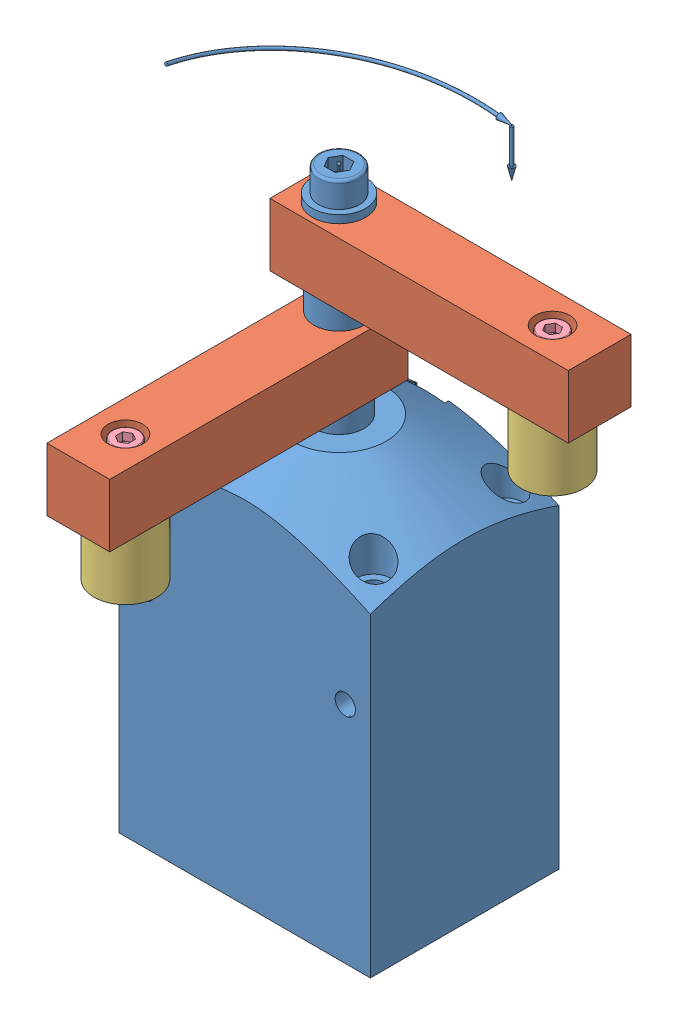
SolidWorks assembly assemb_pneu_clamp_v3, configuration Default. Lengths in mm.
Overall size (138.53 190.01 139).
9 component instances, 4 part files, 6 mates.
Components (placement in the parent):
- clamping_body_cw-1: clamping_body_cw [Default] at (67.3123 178.5452 175.0811) x (-1 0 0) z (0 1 0) size (95.58 86.05 190.01)
- assemb_braco_v3-1: assemb_braco_v3 [Default] at (78.3965 110.7532 94.4609) size (95 40 21.92)
  - clamping_arm_sp_v3-1: clamping_arm_sp_v3 [Default] at (-11.0842 57.292 80.6201) x (1 0 0) z (0 1 0) size (95 20 20)
  - contact_end_full-1: contact_end_full [Default] at (56.9158 17.292 80.6201) x (0.994886 0 -0.101006) z (0.101006 0 0.994886) size (20 25 20)
  - socket head cap screw_iso-2: socket head cap screw_iso [ISO 4762 M5 x 16 - 16N] at (56.9158 56.292 80.6201) x (0 -1 0) z (0 0 1) size (21 8.5 8.5)
- assemb_braco_v3-2: assemb_braco_v3 [Default] at (147.9324 80.7532 186.1653) x (0 0 1) z (-1 0 0) size (95 40 21.92)
  - clamping_arm_sp_v3-1: clamping_arm_sp_v3 [Default] at (-11.0842 57.292 80.6201) x (1 0 0) z (0 1 0) size (95 20 20)
  - contact_end_full-1: contact_end_full [Default] at (56.9158 17.292 80.6201) x (0.994886 0 -0.101006) z (0.101006 0 0.994886) size (20 25 20)
  - socket head cap screw_iso-2: socket head cap screw_iso [ISO 4762 M5 x 16 - 16N] at (56.9158 56.292 80.6201) x (0 -1 0) z (0 0 1) size (21 8.5 8.5)
Mates (geometry in assembly coordinates):
- Concentric1: concentric aligned: cone of clamping_body_cw-1 through (67.3123 166.0452 175.0811) axis (0 1 0); cone of assemb_braco_v3-1/clamping_arm_sp_v3-1 through (67.3123 168.0452 175.0811) axis (0 1 0)
- Parallel1: parallel aligned: plane of clamping_body_cw-1 through (107.3123 -10.9548 145.0811) normal (1 0 0); plane of assemb_braco_v3-1/clamping_arm_sp_v3-1 through (150.3123 148.0452 165.0811) normal (1 0 0)
- Coincident2: coincident aligned: circle of clamping_body_cw-1; plane of assemb_braco_v3-1/clamping_arm_sp_v3-1 through (55.3123 148.0452 185.0811) normal (0 -1 0)
- Concentric2: concentric anti-aligned: cylinder of clamping_body_cw-1 through (67.3123 108.5665 175.0811) axis (0 -1 0) radius 8; cone of assemb_braco_v3-2/clamping_arm_sp_v3-1 through (67.3123 138.0452 175.0811) axis (0 1 0)
- Parallel2: parallel aligned: plane of clamping_body_cw-1 through (107.3123 109.5452 205.0811) normal (0 0 1); plane of assemb_braco_v3-2/clamping_arm_sp_v3-1 through (77.3123 118.0452 258.0811) normal (0 0 1)
- Distance1: distance = 30 mm aligned: plane of assemb_braco_v3-2/clamping_arm_sp_v3-1 through (57.3123 138.0452 163.0811) normal (0 1 0); plane of assemb_braco_v3-1/clamping_arm_sp_v3-1 through (55.3123 168.0452 185.0811) normal (0 1 0)
